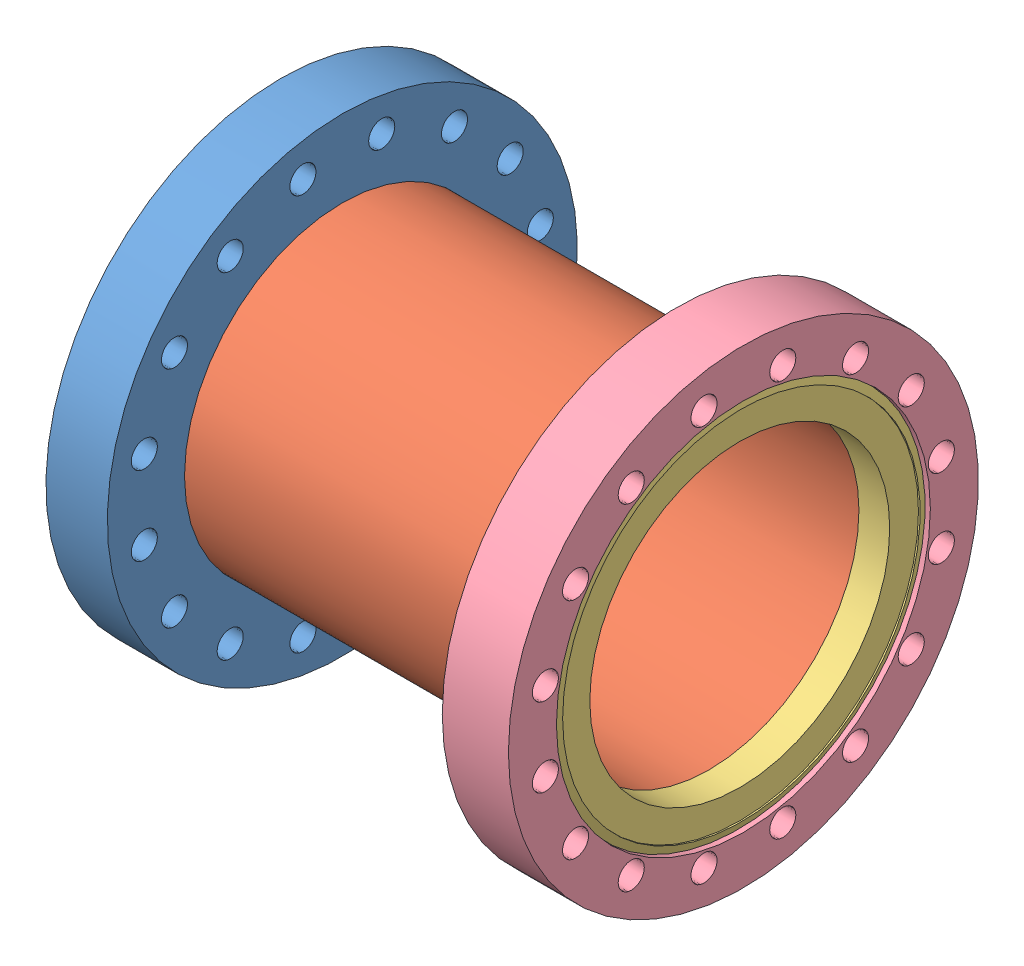
SolidWorks assembly FN-C7137023, configuration Default. Lengths in mm.
Overall size (149.2 151.64 151.64).
5 component instances, 4 part files, 8 mates.
Components (placement in the parent):
- 110026 (6.0 X 4.0 NR)-1: 110026 (6.0 X 4.0 NR) [Default] at origin size (19.81 151.64 151.64)
- wall^FN-C7137023-1: wall^FN-C7137023 [Default] at (11.0998 0 0) x (0 -1 0) z (0 0 1) size (101.6 127 101.6) (virtual)
- 100026 (6.0 X 4.0 R)-1: 100026 (6.0 X 4.0 R) [Default] at (134.8994 0 0) size (21.34 151.64 151.64)
  - 100026 (6.0 X 4.0 INS)-1: 100026 (6.0 X 4.0 INS) [Default] at origin size (13.64 120.4 120.4)
  - 100026 (6.0 X 4.0 REC)-1: 100026 (6.0 X 4.0 REC) [Default] at (-7.0358 0 0) x (1 0 0) z (0 0 -1) size (21.34 151.64 151.64)
Mates (geometry in assembly coordinates):
- Coincident1: coincident aligned: plane of 110026 (6.0 X 4.0 NR)-1 through (0 0 0) normal (0 0 1); plane of assembly through (0 0 0) normal (0 0 1)
- Coincident2: coincident aligned: plane of 110026 (6.0 X 4.0 NR)-1 through (0 0 0) normal (0 1 0); plane of assembly through (0 0 0) normal (0 1 0)
- Coincident3: coincident aligned: plane of 110026 (6.0 X 4.0 NR)-1 through (0 0 0) normal (1 0 0); plane of assembly through (0 0 0) normal (1 0 0)
- Coincident4: coincident anti-aligned: plane of 110026 (6.0 X 4.0 NR)-1 through (11.0998 49.6729 0) normal (1 0 0); plane of wall^FN-C7137023-1 through (11.0998 0 0) normal (-1 0 0)
- Concentric1: concentric anti-aligned: cylinder of 110026 (6.0 X 4.0 NR)-1 through (15.4559 0 0) axis (1 0 0) radius 50.927; cylinder of wall^FN-C7137023-1 through (138.0998 0 0) axis (-1 0 0) radius 50.8
- Coincident5: coincident aligned: plane of wall^FN-C7137023-1 through (11.0998 0 0) normal (0 0 1); plane of assembly
- Coincident6: coincident anti-aligned: plane of wall^FN-C7137023-1 through (138.0998 0 0) normal (1 0 0); plane of 100026 (6.0 X 4.0 R)-1/100026 (6.0 X 4.0 INS)-1 through (138.0998 49.657 0) normal (-1 0 0)
- Concentric2: concentric anti-aligned: cylinder of wall^FN-C7137023-1 through (138.0998 0 0) axis (-1 0 0) radius 50.8; cylinder of 100026 (6.0 X 4.0 R)-1/100026 (6.0 X 4.0 INS)-1 through (136.4996 0 0) axis (1 0 0) radius 50.927
